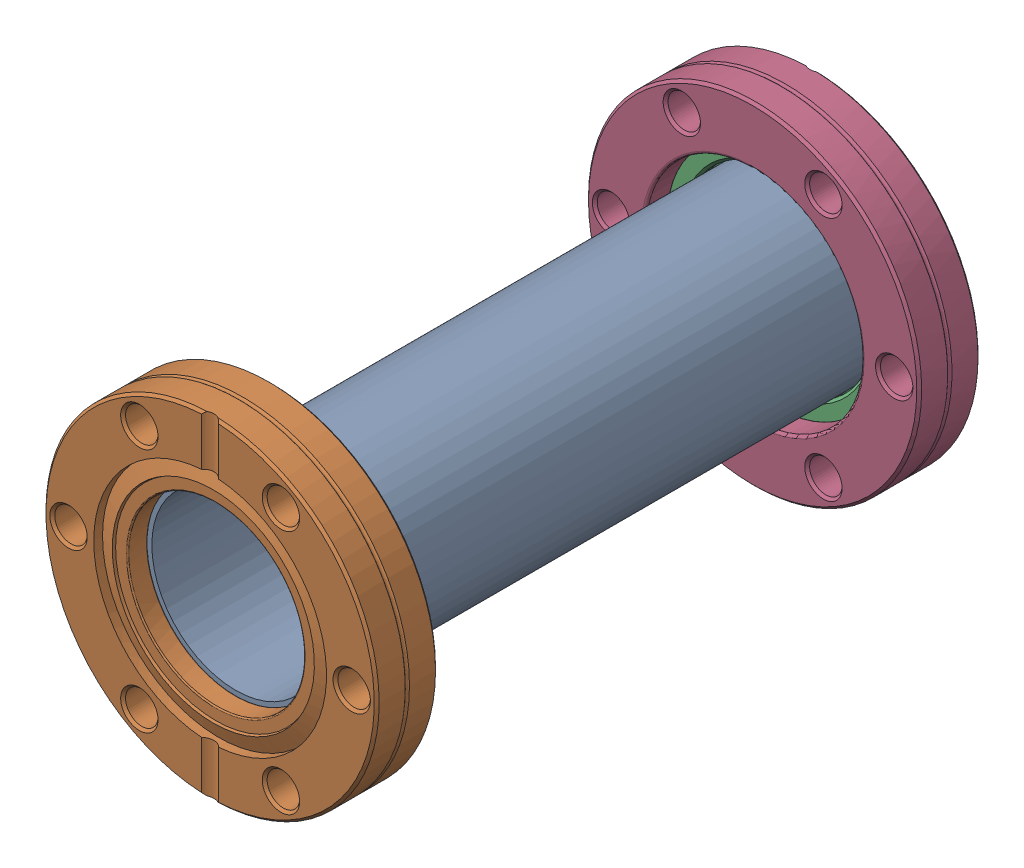
SolidWorks assembly Er Source P2_fn-0275, configuration Default. Lengths in mm.
Overall size (69.09 69.09 125.37).
6 component instances, 4 part files, 0 mates.
Components (placement in the parent):
- Er Source P2-2_A0001676-1: Er Source P2-2_A0001676 [Default] at origin size (69.09 69.09 120.02)
  - Er Source P2-2-2_P0001614-1: Er Source P2-2-2_P0001614 [Default] at (0 0 -56.2483) x (0 1 0) z (0 0 -1) size (38.1 38.1 114.58)
  - Er Source P2-2-1_P0000127-1: Er Source P2-2-1_P0000127 [Default] at origin size (69.09 69.09 12.84)
- A0000603-1: A0000603 [Default] at (0 0 -106.1466) x (1 0 0) z (0 0 -1) size (69.09 69.09 12.74)
  - Er Source P2-1-2_P0000489-1: Er Source P2-1-2_P0000489 [Default] at (0 0 8.5725) size (48.21 48.21 6.99)
  - Er Source P2-1-1_P0000436-1: Er Source P2-1-1_P0000436 [Default] at (0 0 6.35) x (-1 0 0) z (0 0 -1) size (69.09 69.09 12.74)
